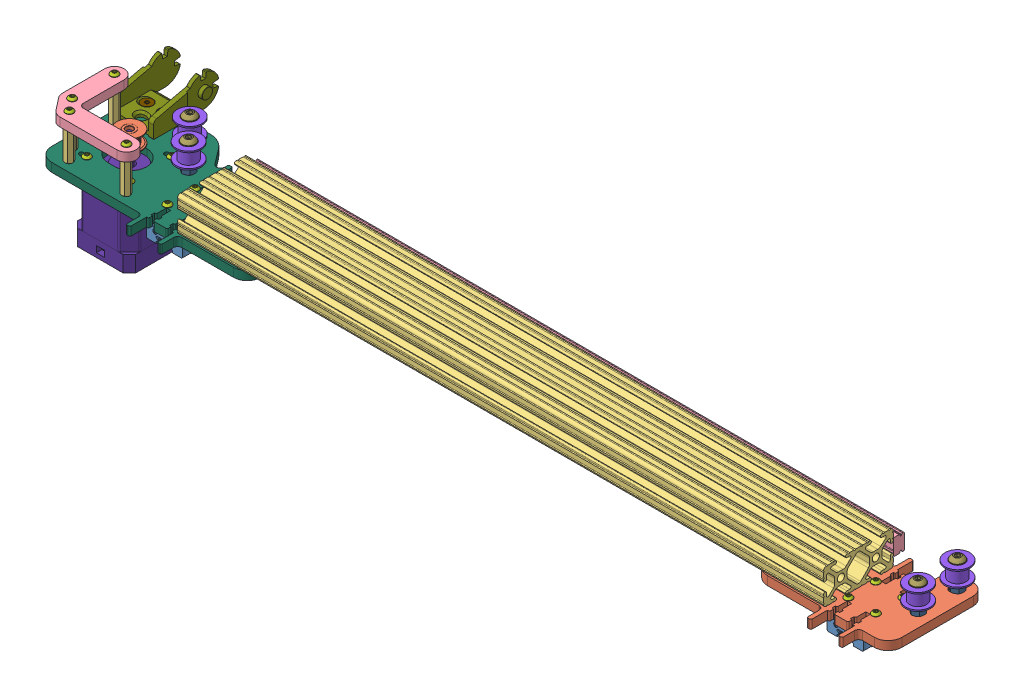
SolidWorks assembly X Axis, configuration Default. Lengths in mm.
Overall size (620.26 87.49 111.65).
113 component instances, 22 part files, 109 mates.
Components (placement in the parent):
- Hiwin-MGN12HZFC-1: Hiwin-MGN12HZFC [Default] at (247.7 -5 0) x (0 0 1) z (0 1 0) size (45.6 27 10)
- X Axis Idler Plate-1: X Axis Idler Plate [Default] at (222.3 5 22.7) x (-1 0 0) z (0 0 -1) size (97.84 6.35 82.44)
- Rail Mount-1: Rail Mount [Default] at (0 24.05 22.7) x (0 0 -1) z (-1 0 0) size (58.8 25.4 470)
  - 1020 Rail Support-1: 1020 Rail Support [1020] at (12.7 0 0) size (50.8 25.4 470)
  - Hiwin-MGNR12R470CM-1: Hiwin-MGNR12R470CM [Default] at (25.4 0 225) x (0 0 -1) z (1 0 0) size (470 12 8.07)
  - 91290A115_M3x10 BLACK-OXIDE CLASS 12.9 SOCKET HEAD CAP SCREW-20: 91290A115_M3x10 BLACK-OXIDE CLASS 12.9 SOCKET HEAD CAP SCREW [91290A115] at (18.9 0 225) x (0 0 1) z (-1 0 0) size (5.5 5.5 13.21)
  - 91290A115_M3x10 BLACK-OXIDE CLASS 12.9 SOCKET HEAD CAP SCREW-21: 91290A115_M3x10 BLACK-OXIDE CLASS 12.9 SOCKET HEAD CAP SCREW [91290A115] at (18.9 0 200) x (0 0 1) z (-1 0 0) size (5.5 5.5 13.21)
  - 91290A115_M3x10 BLACK-OXIDE CLASS 12.9 SOCKET HEAD CAP SCREW-22: 91290A115_M3x10 BLACK-OXIDE CLASS 12.9 SOCKET HEAD CAP SCREW [91290A115] at (18.9 0 175) x (0 0 1) z (-1 0 0) size (5.5 5.5 13.21)
  - 91290A115_M3x10 BLACK-OXIDE CLASS 12.9 SOCKET HEAD CAP SCREW-23: 91290A115_M3x10 BLACK-OXIDE CLASS 12.9 SOCKET HEAD CAP SCREW [91290A115] at (18.9 0 150) x (0 0 1) z (-1 0 0) size (5.5 5.5 13.21)
  - 91290A115_M3x10 BLACK-OXIDE CLASS 12.9 SOCKET HEAD CAP SCREW-24: 91290A115_M3x10 BLACK-OXIDE CLASS 12.9 SOCKET HEAD CAP SCREW [91290A115] at (18.9 0 125) x (0 0 1) z (-1 0 0) size (5.5 5.5 13.21)
  - 91290A115_M3x10 BLACK-OXIDE CLASS 12.9 SOCKET HEAD CAP SCREW-25: 91290A115_M3x10 BLACK-OXIDE CLASS 12.9 SOCKET HEAD CAP SCREW [91290A115] at (18.9 0 100) x (0 0 1) z (-1 0 0) size (5.5 5.5 13.21)
  - 91290A115_M3x10 BLACK-OXIDE CLASS 12.9 SOCKET HEAD CAP SCREW-26: 91290A115_M3x10 BLACK-OXIDE CLASS 12.9 SOCKET HEAD CAP SCREW [91290A115] at (18.9 0 75) x (0 0 1) z (-1 0 0) size (5.5 5.5 13.21)
  - 91290A115_M3x10 BLACK-OXIDE CLASS 12.9 SOCKET HEAD CAP SCREW-27: 91290A115_M3x10 BLACK-OXIDE CLASS 12.9 SOCKET HEAD CAP SCREW [91290A115] at (18.9 0 50) x (0 0 1) z (-1 0 0) size (5.5 5.5 13.21)
  - 91290A115_M3x10 BLACK-OXIDE CLASS 12.9 SOCKET HEAD CAP SCREW-28: 91290A115_M3x10 BLACK-OXIDE CLASS 12.9 SOCKET HEAD CAP SCREW [91290A115] at (18.9 0 25) x (0 0 1) z (-1 0 0) size (5.5 5.5 13.21)
  - 91290A115_M3x10 BLACK-OXIDE CLASS 12.9 SOCKET HEAD CAP SCREW-29: 91290A115_M3x10 BLACK-OXIDE CLASS 12.9 SOCKET HEAD CAP SCREW [91290A115] at (18.9 0 0) x (0 0 1) z (-1 0 0) size (5.5 5.5 13.21)
  - 91290A115_M3x10 BLACK-OXIDE CLASS 12.9 SOCKET HEAD CAP SCREW-30: 91290A115_M3x10 BLACK-OXIDE CLASS 12.9 SOCKET HEAD CAP SCREW [91290A115] at (18.9 0 -25) x (0 0 1) z (-1 0 0) size (5.5 5.5 13.21)
  - 91290A115_M3x10 BLACK-OXIDE CLASS 12.9 SOCKET HEAD CAP SCREW-31: 91290A115_M3x10 BLACK-OXIDE CLASS 12.9 SOCKET HEAD CAP SCREW [91290A115] at (18.9 0 -50) x (0 0 1) z (-1 0 0) size (5.5 5.5 13.21)
  - 91290A115_M3x10 BLACK-OXIDE CLASS 12.9 SOCKET HEAD CAP SCREW-32: 91290A115_M3x10 BLACK-OXIDE CLASS 12.9 SOCKET HEAD CAP SCREW [91290A115] at (18.9 0 -75) x (0 0 1) z (-1 0 0) size (5.5 5.5 13.21)
  - 91290A115_M3x10 BLACK-OXIDE CLASS 12.9 SOCKET HEAD CAP SCREW-33: 91290A115_M3x10 BLACK-OXIDE CLASS 12.9 SOCKET HEAD CAP SCREW [91290A115] at (18.9 0 -100) x (0 0 1) z (-1 0 0) size (5.5 5.5 13.21)
  - 91290A115_M3x10 BLACK-OXIDE CLASS 12.9 SOCKET HEAD CAP SCREW-34: 91290A115_M3x10 BLACK-OXIDE CLASS 12.9 SOCKET HEAD CAP SCREW [91290A115] at (18.9 0 -125) x (0 0 1) z (-1 0 0) size (5.5 5.5 13.21)
  - 91290A115_M3x10 BLACK-OXIDE CLASS 12.9 SOCKET HEAD CAP SCREW-35: 91290A115_M3x10 BLACK-OXIDE CLASS 12.9 SOCKET HEAD CAP SCREW [91290A115] at (18.9 0 -150) x (0 0 1) z (-1 0 0) size (5.5 5.5 13.21)
  - 91290A115_M3x10 BLACK-OXIDE CLASS 12.9 SOCKET HEAD CAP SCREW-36: 91290A115_M3x10 BLACK-OXIDE CLASS 12.9 SOCKET HEAD CAP SCREW [91290A115] at (18.9 0 -175) x (0 0 1) z (-1 0 0) size (5.5 5.5 13.21)
  - 91290A115_M3x10 BLACK-OXIDE CLASS 12.9 SOCKET HEAD CAP SCREW-37: 91290A115_M3x10 BLACK-OXIDE CLASS 12.9 SOCKET HEAD CAP SCREW [91290A115] at (18.9 0 -200) x (0 0 1) z (-1 0 0) size (5.5 5.5 13.21)
  - 91290A115_M3x10 BLACK-OXIDE CLASS 12.9 SOCKET HEAD CAP SCREW-38: 91290A115_M3x10 BLACK-OXIDE CLASS 12.9 SOCKET HEAD CAP SCREW [91290A115] at (18.9 0 -225) x (0 0 1) z (-1 0 0) size (5.5 5.5 13.21)
  - M3 T slot nut-ebay262350716437-1: M3 T slot nut-ebay262350716437 [Default] at (23.6902 0 228) x (0 1 0) z (0 0 -1) size (10 4 6)
  - M3 T slot nut-ebay262350716437-2: M3 T slot nut-ebay262350716437 [Default] at (23.6902 0 203) x (0 1 0) z (0 0 -1) size (10 4 6)
  - M3 T slot nut-ebay262350716437-3: M3 T slot nut-ebay262350716437 [Default] at (23.6902 0 178) x (0 1 0) z (0 0 -1) size (10 4 6)
  - M3 T slot nut-ebay262350716437-4: M3 T slot nut-ebay262350716437 [Default] at (23.6902 0 153) x (0 1 0) z (0 0 -1) size (10 4 6)
  - M3 T slot nut-ebay262350716437-5: M3 T slot nut-ebay262350716437 [Default] at (23.6902 0 128) x (0 1 0) z (0 0 -1) size (10 4 6)
  - M3 T slot nut-ebay262350716437-6: M3 T slot nut-ebay262350716437 [Default] at (23.6902 0 103) x (0 1 0) z (0 0 -1) size (10 4 6)
  - M3 T slot nut-ebay262350716437-7: M3 T slot nut-ebay262350716437 [Default] at (23.6902 0 78) x (0 1 0) z (0 0 -1) size (10 4 6)
  - M3 T slot nut-ebay262350716437-8: M3 T slot nut-ebay262350716437 [Default] at (23.6902 0 53) x (0 1 0) z (0 0 -1) size (10 4 6)
  - M3 T slot nut-ebay262350716437-9: M3 T slot nut-ebay262350716437 [Default] at (23.6902 0 28) x (0 1 0) z (0 0 -1) size (10 4 6)
  - M3 T slot nut-ebay262350716437-10: M3 T slot nut-ebay262350716437 [Default] at (23.6902 0 3) x (0 1 0) z (0 0 -1) size (10 4 6)
  - M3 T slot nut-ebay262350716437-11: M3 T slot nut-ebay262350716437 [Default] at (23.6902 0 -22) x (0 1 0) z (0 0 -1) size (10 4 6)
  - M3 T slot nut-ebay262350716437-12: M3 T slot nut-ebay262350716437 [Default] at (23.6902 0 -47) x (0 1 0) z (0 0 -1) size (10 4 6)
  - M3 T slot nut-ebay262350716437-13: M3 T slot nut-ebay262350716437 [Default] at (23.6902 0 -72) x (0 1 0) z (0 0 -1) size (10 4 6)
  - M3 T slot nut-ebay262350716437-14: M3 T slot nut-ebay262350716437 [Default] at (23.6902 0 -97) x (0 1 0) z (0 0 -1) size (10 4 6)
  - M3 T slot nut-ebay262350716437-15: M3 T slot nut-ebay262350716437 [Default] at (23.6902 0 -122) x (0 1 0) z (0 0 -1) size (10 4 6)
  - M3 T slot nut-ebay262350716437-16: M3 T slot nut-ebay262350716437 [Default] at (23.6902 0 -147) x (0 1 0) z (0 0 -1) size (10 4 6)
  - M3 T slot nut-ebay262350716437-17: M3 T slot nut-ebay262350716437 [Default] at (23.6902 0 -172) x (0 1 0) z (0 0 -1) size (10 4 6)
  - M3 T slot nut-ebay262350716437-18: M3 T slot nut-ebay262350716437 [Default] at (23.6902 0 -197) x (0 1 0) z (0 0 -1) size (10 4 6)
  - M3 T slot nut-ebay262350716437-19: M3 T slot nut-ebay262350716437 [Default] at (23.6902 0 -222) x (0 1 0) z (0 0 -1) size (10 4 6)
- 91239A115_M3x10 CLASS 10.9 STL BUTTON-HEAD SOCKET CAP SCREW-14: 91239A115_M3x10 CLASS 10.9 STL BUTTON-HEAD SOCKET CAP SCREW [91239A115] at (237.7 13 32.7) x (1 0 0) z (0 1 0) size (5.7 5.7 11.96)
- 91239A115_M3x10 CLASS 10.9 STL BUTTON-HEAD SOCKET CAP SCREW-17: 91239A115_M3x10 CLASS 10.9 STL BUTTON-HEAD SOCKET CAP SCREW [91239A115] at (237.7 13 12.7) x (1 0 0) z (0 1 0) size (5.7 5.7 11.96)
- 91239A115_M3x10 CLASS 10.9 STL BUTTON-HEAD SOCKET CAP SCREW-15: 91239A115_M3x10 CLASS 10.9 STL BUTTON-HEAD SOCKET CAP SCREW [91239A115] at (257.7 13 32.7) x (1 0 0) z (0 1 0) size (5.7 5.7 11.96)
- 91239A115_M3x10 CLASS 10.9 STL BUTTON-HEAD SOCKET CAP SCREW-16: 91239A115_M3x10 CLASS 10.9 STL BUTTON-HEAD SOCKET CAP SCREW [91239A115] at (257.7 13 12.7) x (1 0 0) z (0 1 0) size (5.7 5.7 11.96)
- 20T Idler Pulley wBearing-1: 20T Idler Pulley wBearing [Default] at (272.04 24.05 16.34) x (0.994803 0 0.101817) z (-0.101817 0 0.994803) size (18 33.32 18)
  - Powge 20T Idler Pulley-1: Powge 20T Idler Pulley [Default] at origin size (18 12 18)
  - 7804K106_STAINLESS STEEL BALL BEARING-1: 7804K106_STAINLESS STEEL BALL BEARING [7804K106] at (0 4 0) x (1 0 0) z (0 -1 0) size (10 10 4)
  - 7804K106_STAINLESS STEEL BALL BEARING-2: 7804K106_STAINLESS STEEL BALL BEARING [7804K106] at (0 -4 0) x (-1 0 0) z (0 1 0) size (10 10 4)
  - 90591A146_M5 ZINC PLATED STEEL HEX NUT-1: 90591A146_M5 ZINC PLATED STEEL HEX NUT [90591A146] at (0 -10.7 0) x (1 0 0) z (0 1 0) size (8 9.24 4.46)
  - 90695A037_M5 CLASS 04 STEEL THIN HEX NUT - DIN 439B-1: 90695A037_M5 CLASS 04 STEEL THIN HEX NUT - DIN 439B [90695A037] at (0 -7.35 0) size (8 3.32 9.24)
  - 91239A236_M5x30 CLASS 10.9 STL BUTTON-HEAD SOCKET CAP SCREW-1: 91239A236_M5x30 CLASS 10.9 STL BUTTON-HEAD SOCKET CAP SCREW [91239A236] at (0 8.75 0) x (1 0 0) z (0 1 0) size (9.5 9.5 33.32)
- 90576A104_M5 ZINC-PLATED CLASS 8 STL NYLON-INSERT LOCKNUT-1: 90576A104_M5 ZINC-PLATED CLASS 8 STL NYLON-INSERT LOCKNUT [90576A104] at (272.04 5 16.34) x (0.923728 0 -0.383049) z (-0.383049 0 -0.923728) size (8 5.15 9.24)
- 20T Idler Pulley wBearing-2: 20T Idler Pulley wBearing [Default] at (272.04 24.05 -12.34) x (0.994803 0 0.101817) z (-0.101817 0 0.994803) size (18 33.32 18)
  - Powge 20T Idler Pulley-1: Powge 20T Idler Pulley [Default] at origin size (18 12 18)
  - 7804K106_STAINLESS STEEL BALL BEARING-1: 7804K106_STAINLESS STEEL BALL BEARING [7804K106] at (0 4 0) x (1 0 0) z (0 -1 0) size (10 10 4)
  - 7804K106_STAINLESS STEEL BALL BEARING-2: 7804K106_STAINLESS STEEL BALL BEARING [7804K106] at (0 -4 0) x (-1 0 0) z (0 1 0) size (10 10 4)
  - 90591A146_M5 ZINC PLATED STEEL HEX NUT-1: 90591A146_M5 ZINC PLATED STEEL HEX NUT [90591A146] at (0 -10.7 0) x (1 0 0) z (0 1 0) size (8 9.24 4.46)
  - 90695A037_M5 CLASS 04 STEEL THIN HEX NUT - DIN 439B-1: 90695A037_M5 CLASS 04 STEEL THIN HEX NUT - DIN 439B [90695A037] at (0 -7.35 0) size (8 3.32 9.24)
  - 91239A236_M5x30 CLASS 10.9 STL BUTTON-HEAD SOCKET CAP SCREW-1: 91239A236_M5x30 CLASS 10.9 STL BUTTON-HEAD SOCKET CAP SCREW [91239A236] at (0 8.75 0) x (1 0 0) z (0 1 0) size (9.5 9.5 33.32)
- 90576A104_M5 ZINC-PLATED CLASS 8 STL NYLON-INSERT LOCKNUT-2: 90576A104_M5 ZINC-PLATED CLASS 8 STL NYLON-INSERT LOCKNUT [90576A104] at (272.04 5 -12.34) x (0.923728 0 -0.383049) z (-0.383049 0 -0.923728) size (8 5.15 9.24)
- 91239A228_M5x12 CLASS 10.9 STL BUTTON-HEAD SOCKET CAP SCREW-1: 91239A228_M5x12 CLASS 10.9 STL BUTTON-HEAD SOCKET CAP SCREW [91239A228] at (196.9 2.25 10) x (0.396762 0 -0.917922) z (0 -1 0) size (9.5 9.5 15.22)
- 91239A228_M5x12 CLASS 10.9 STL BUTTON-HEAD SOCKET CAP SCREW-2: 91239A228_M5x12 CLASS 10.9 STL BUTTON-HEAD SOCKET CAP SCREW [91239A228] at (222.3 2.25 10) x (1 0 0) z (0 -1 0) size (9.5 9.5 15.22)
- 91239A228_M5x12 CLASS 10.9 STL BUTTON-HEAD SOCKET CAP SCREW-3: 91239A228_M5x12 CLASS 10.9 STL BUTTON-HEAD SOCKET CAP SCREW [91239A228] at (196.9 2.25 35.4) x (1 0 0) z (0 -1 0) size (9.5 9.5 15.22)
- 91239A228_M5x12 CLASS 10.9 STL BUTTON-HEAD SOCKET CAP SCREW-4: 91239A228_M5x12 CLASS 10.9 STL BUTTON-HEAD SOCKET CAP SCREW [91239A228] at (222.3 2.25 35.4) x (1 0 0) z (0 -1 0) size (9.5 9.5 15.22)
- X Axis Motor Plate-1: X Axis Motor Plate [Default] at (-222.3 5 22.7) x (-1 0 0) z (0 0 -1) size (152.42 6.35 87.44)
- Hiwin-MGN12HZFC-2: Hiwin-MGN12HZFC [Default] at (-247.7 -5 0) x (0 0 1) z (0 1 0) size (45.6 27 10)
- 91239A115_M3x10 CLASS 10.9 STL BUTTON-HEAD SOCKET CAP SCREW-18: 91239A115_M3x10 CLASS 10.9 STL BUTTON-HEAD SOCKET CAP SCREW [91239A115] at (-257.7 13 32.7) x (1 0 0) z (0 1 0) size (5.7 5.7 11.96)
- 91239A115_M3x10 CLASS 10.9 STL BUTTON-HEAD SOCKET CAP SCREW-8: 91239A115_M3x10 CLASS 10.9 STL BUTTON-HEAD SOCKET CAP SCREW [91239A115] at (-237.7 13 32.7) x (1 0 0) z (0 1 0) size (5.7 5.7 11.96)
- 91239A115_M3x10 CLASS 10.9 STL BUTTON-HEAD SOCKET CAP SCREW-7: 91239A115_M3x10 CLASS 10.9 STL BUTTON-HEAD SOCKET CAP SCREW [91239A115] at (-237.7 13 12.7) x (1 0 0) z (0 1 0) size (5.7 5.7 11.96)
- 91239A115_M3x10 CLASS 10.9 STL BUTTON-HEAD SOCKET CAP SCREW-12: 91239A115_M3x10 CLASS 10.9 STL BUTTON-HEAD SOCKET CAP SCREW [91239A115] at (-257.7 13 12.7) x (1 0 0) z (0 1 0) size (5.7 5.7 11.96)
- 20T Idler Pulley wBearing-3: 20T Idler Pulley wBearing [Default] at (-271.4 24.05 3.62) x (0.994803 0 0.101817) z (-0.101817 0 0.994803) size (18 33.32 18)
  - Powge 20T Idler Pulley-1: Powge 20T Idler Pulley [Default] at origin size (18 12 18)
  - 7804K106_STAINLESS STEEL BALL BEARING-1: 7804K106_STAINLESS STEEL BALL BEARING [7804K106] at (0 4 0) x (1 0 0) z (0 -1 0) size (10 10 4)
  - 7804K106_STAINLESS STEEL BALL BEARING-2: 7804K106_STAINLESS STEEL BALL BEARING [7804K106] at (0 -4 0) x (-1 0 0) z (0 1 0) size (10 10 4)
  - 90591A146_M5 ZINC PLATED STEEL HEX NUT-1: 90591A146_M5 ZINC PLATED STEEL HEX NUT [90591A146] at (0 -10.7 0) x (1 0 0) z (0 1 0) size (8 9.24 4.46)
  - 90695A037_M5 CLASS 04 STEEL THIN HEX NUT - DIN 439B-1: 90695A037_M5 CLASS 04 STEEL THIN HEX NUT - DIN 439B [90695A037] at (0 -7.35 0) size (8 3.32 9.24)
  - 91239A236_M5x30 CLASS 10.9 STL BUTTON-HEAD SOCKET CAP SCREW-1: 91239A236_M5x30 CLASS 10.9 STL BUTTON-HEAD SOCKET CAP SCREW [91239A236] at (0 8.75 0) x (1 0 0) z (0 1 0) size (9.5 9.5 33.32)
- 20T Idler Pulley wBearing-4: 20T Idler Pulley wBearing [Default] at (-286.5419 24.05 -12.34) x (0.994803 0 0.101817) z (-0.101817 0 0.994803) size (18 33.32 18)
  - Powge 20T Idler Pulley-1: Powge 20T Idler Pulley [Default] at origin size (18 12 18)
  - 7804K106_STAINLESS STEEL BALL BEARING-1: 7804K106_STAINLESS STEEL BALL BEARING [7804K106] at (0 4 0) x (1 0 0) z (0 -1 0) size (10 10 4)
  - 7804K106_STAINLESS STEEL BALL BEARING-2: 7804K106_STAINLESS STEEL BALL BEARING [7804K106] at (0 -4 0) x (-1 0 0) z (0 1 0) size (10 10 4)
  - 90591A146_M5 ZINC PLATED STEEL HEX NUT-1: 90591A146_M5 ZINC PLATED STEEL HEX NUT [90591A146] at (0 -10.7 0) x (1 0 0) z (0 1 0) size (8 9.24 4.46)
  - 90695A037_M5 CLASS 04 STEEL THIN HEX NUT - DIN 439B-1: 90695A037_M5 CLASS 04 STEEL THIN HEX NUT - DIN 439B [90695A037] at (0 -7.35 0) size (8 3.32 9.24)
  - 91239A236_M5x30 CLASS 10.9 STL BUTTON-HEAD SOCKET CAP SCREW-1: 91239A236_M5x30 CLASS 10.9 STL BUTTON-HEAD SOCKET CAP SCREW [91239A236] at (0 8.75 0) x (1 0 0) z (0 1 0) size (9.5 9.5 33.32)
- Drag Chain 18x25mm End-1: Drag Chain 18x25mm End [Default] at (-319.9712 11.35 -3.16) size (36.5 22.67 48.39)
- Nema17-1200mA-Stepper-1: Nema17-1200mA-Stepper [Default] at (-301.7597 -43 16.34) size (42.3 70.03 42.3)
- 91239A115_M3x10 CLASS 10.9 STL BUTTON-HEAD SOCKET CAP SCREW-9: 91239A115_M3x10 CLASS 10.9 STL BUTTON-HEAD SOCKET CAP SCREW [91239A115] at (-286.2597 13 31.84) x (1 0 0) z (0 1 0) size (5.7 5.7 11.96)
- 91239A115_M3x10 CLASS 10.9 STL BUTTON-HEAD SOCKET CAP SCREW-10: 91239A115_M3x10 CLASS 10.9 STL BUTTON-HEAD SOCKET CAP SCREW [91239A115] at (-317.2597 13 31.84) x (1 0 0) z (0 1 0) size (5.7 5.7 11.96)
- 91239A115_M3x10 CLASS 10.9 STL BUTTON-HEAD SOCKET CAP SCREW-11: 91239A115_M3x10 CLASS 10.9 STL BUTTON-HEAD SOCKET CAP SCREW [91239A115] at (-317.2597 13 0.84) x (1 0 0) z (0 1 0) size (5.7 5.7 11.96)
- 91239A115_M3x10 CLASS 10.9 STL BUTTON-HEAD SOCKET CAP SCREW-13: 91239A115_M3x10 CLASS 10.9 STL BUTTON-HEAD SOCKET CAP SCREW [91239A115] at (-286.2597 13 0.84) x (1 0 0) z (0 1 0) size (5.7 5.7 11.96)
- 91294A194_M4x16 BLACK ALLOY STEEL FLAT-HEAD SOCKET CAP SCREW-4: 91294A194_M4x16 BLACK ALLOY STEEL FLAT-HEAD SOCKET CAP SCREW [91294A194] at (-313.7212 14.85 -20.91) x (1 0 0) z (0 1 0) size (8 8 16.42)
- 91294A194_M4x16 BLACK ALLOY STEEL FLAT-HEAD SOCKET CAP SCREW-5: 91294A194_M4x16 BLACK ALLOY STEEL FLAT-HEAD SOCKET CAP SCREW [91294A194] at (-326.2212 14.85 -20.91) x (1 0 0) z (0 1 0) size (8 8 16.42)
- 90576A103_M4 ZINC-PLATED CLASS 8 STL NYLON-INSERT LOCKNUT-1: 90576A103_M4 ZINC-PLATED CLASS 8 STL NYLON-INSERT LOCKNUT [90576A103] at (-313.7212 5 -20.91) x (-0.837169 0 -0.546944) z (-0.546944 0 0.837169) size (7 5.12 8.08)
- 90576A103_M4 ZINC-PLATED CLASS 8 STL NYLON-INSERT LOCKNUT-2: 90576A103_M4 ZINC-PLATED CLASS 8 STL NYLON-INSERT LOCKNUT [90576A103] at (-326.2212 5 -20.91) x (0.272867 0 0.962052) z (0.962052 0 -0.272867) size (7 5.12 8.08)
- GT2_20tooth-1: GT2_20tooth [Default] at (-301.7597 11.55 16.34) x (0 1 0) z (-0.782139 0 -0.623104) size (17.5 18 18)
- 90576A103_M4 ZINC-PLATED CLASS 8 STL NYLON-INSERT LOCKNUT-3: 90576A103_M4 ZINC-PLATED CLASS 8 STL NYLON-INSERT LOCKNUT [90576A103] at (-286.5419 5 -12.34) x (-0.837169 0 -0.546944) z (-0.546944 0 0.837169) size (7 5.12 8.08)
- 90576A103_M4 ZINC-PLATED CLASS 8 STL NYLON-INSERT LOCKNUT-4: 90576A103_M4 ZINC-PLATED CLASS 8 STL NYLON-INSERT LOCKNUT [90576A103] at (-271.4 5 3.62) x (-0.837169 0 -0.546944) z (-0.546944 0 0.837169) size (7 5.12 8.08)
- M4x25 standoff-1: M4x25 standoff [Default] at (-321.1212 11.35 40.84) size (6.93 25 6)
- M4x25 standoff-2: M4x25 standoff [Default] at (-327.8666 11.35 31.84) size (6.93 25 6)
- M4x25 standoff-3: M4x25 standoff [Default] at (-327.8666 11.35 1.09) size (6.93 25 6)
- M4x25 standoff-4: M4x25 standoff [Default] at (-279.6212 11.35 40.84) size (6.93 25 6)
- 91239A115_M3x10 CLASS 10.9 STL BUTTON-HEAD SOCKET CAP SCREW-22: 91239A115_M3x10 CLASS 10.9 STL BUTTON-HEAD SOCKET CAP SCREW [91239A115] at (-327.8666 3.35 1.09) x (-0.837169 0 -0.546944) z (0 -1 0) size (5.7 5.7 11.96)
- 91239A115_M3x10 CLASS 10.9 STL BUTTON-HEAD SOCKET CAP SCREW-23: 91239A115_M3x10 CLASS 10.9 STL BUTTON-HEAD SOCKET CAP SCREW [91239A115] at (-327.8666 3.35 31.84) x (-0.837169 0 -0.546944) z (0 -1 0) size (5.7 5.7 11.96)
- 91239A115_M3x10 CLASS 10.9 STL BUTTON-HEAD SOCKET CAP SCREW-24: 91239A115_M3x10 CLASS 10.9 STL BUTTON-HEAD SOCKET CAP SCREW [91239A115] at (-321.1212 3.35 40.84) x (-0.837169 0 -0.546944) z (0 -1 0) size (5.7 5.7 11.96)
- 91239A115_M3x10 CLASS 10.9 STL BUTTON-HEAD SOCKET CAP SCREW-25: 91239A115_M3x10 CLASS 10.9 STL BUTTON-HEAD SOCKET CAP SCREW [91239A115] at (-279.6212 3.35 40.84) x (-0.837169 0 -0.546944) z (0 -1 0) size (5.7 5.7 11.96)
- X Axis Cable Guide Top-1: X Axis Cable Guide Top [Default] at (-320.8666 36.35 40.84) x (1 0 0) z (0 1 0) size (62.5 53.75 6.35)
- 91239A115_M3x10 CLASS 10.9 STL BUTTON-HEAD SOCKET CAP SCREW-26: 91239A115_M3x10 CLASS 10.9 STL BUTTON-HEAD SOCKET CAP SCREW [91239A115] at (-327.8666 44.35 1.09) x (1 0 0) z (0 1 0) size (5.7 5.7 11.96)
- 91239A115_M3x10 CLASS 10.9 STL BUTTON-HEAD SOCKET CAP SCREW-27: 91239A115_M3x10 CLASS 10.9 STL BUTTON-HEAD SOCKET CAP SCREW [91239A115] at (-327.8666 44.35 31.84) x (1 0 0) z (0 1 0) size (5.7 5.7 11.96)
- 91239A115_M3x10 CLASS 10.9 STL BUTTON-HEAD SOCKET CAP SCREW-28: 91239A115_M3x10 CLASS 10.9 STL BUTTON-HEAD SOCKET CAP SCREW [91239A115] at (-320.8666 44.35 40.84) x (1 0 0) z (0 1 0) size (5.7 5.7 11.96)
- 91239A115_M3x10 CLASS 10.9 STL BUTTON-HEAD SOCKET CAP SCREW-29: 91239A115_M3x10 CLASS 10.9 STL BUTTON-HEAD SOCKET CAP SCREW [91239A115] at (-279.3666 44.35 40.84) x (1 0 0) z (0 1 0) size (5.7 5.7 11.96)
Mates (geometry in assembly coordinates):
- Coincident1: coincident anti-aligned: plane of Hiwin-MGN12HZFC-1 through (254.1 5 6.5) normal (0 1 0); plane of X Axis Idler Plate-1 through (222.3 5 22.7) normal (0 -1 0)
- Concentric3: concentric anti-aligned: cylinder of Hiwin-MGN12HZFC-1 through (237.7 1.0625 12.7) axis (0 -1 0) radius 1.2295; cylinder of X Axis Idler Plate-1 through (237.7 11.35 12.7) axis (0 1 0) radius 1.7
- Concentric4: concentric anti-aligned: cylinder of Hiwin-MGN12HZFC-1 through (257.7 1.0625 32.7) axis (0 -1 0) radius 1.2295; cylinder of X Axis Idler Plate-1 through (257.7 11.35 32.7) axis (0 1 0) radius 1.7
- Parallel1: parallel aligned: plane of X Axis Idler Plate-1 through (184.2 11.35 -2.7) normal (0 0 -1); plane of Rail Mount-1/Hiwin-MGNR12R470CM-1 through (235 29.55 -10.7) normal (0 0 -1)
- Coincident3: coincident anti-aligned: plane of X Axis Idler Plate-1 through (222.3 11.35 22.7) normal (0 1 0); plane of Rail Mount-1/1020 Rail Support-1 through (235 11.35 20.5664) normal (0 -1 0)
- Coincident4: coincident aligned: plane of X Axis Idler Plate-1 through (184.2 11.35 48.1) normal (0 0 1); plane of Rail Mount-1/1020 Rail Support-1 through (235 14.4996 48.1) normal (0 0 1)
- Distance1: distance = 50.8 mm anti-aligned: plane of Rail Mount-1/1020 Rail Support-1 through (235 12.399 5.7125) normal (1 0 0); plane of X Axis Idler Plate-1 through (184.2 11.35 -2.7) normal (-1 0 0)
- Coincident6: coincident anti-aligned: plane of X Axis Idler Plate-1 through (222.3 11.35 22.7) normal (0 1 0); plane of 91239A115_M3x10 CLASS 10.9 STL BUTTON-HEAD SOCKET CAP SCREW-14 through (237.7 11.35 35.55) normal (0 -1 0)
- Concentric5: concentric aligned: cylinder of X Axis Idler Plate-1 through (237.7 11.35 32.7) axis (0 1 0) radius 1.7; circle of 91239A115_M3x10 CLASS 10.9 STL BUTTON-HEAD SOCKET CAP SCREW-14
- Concentric6: concentric aligned: cylinder of X Axis Idler Plate-1 through (237.7 11.35 12.7) axis (0 1 0) radius 1.7; circle of 91239A115_M3x10 CLASS 10.9 STL BUTTON-HEAD SOCKET CAP SCREW-17
- Concentric7: concentric aligned: cylinder of X Axis Idler Plate-1 through (257.7 11.35 12.7) axis (0 1 0) radius 1.7; circle of 91239A115_M3x10 CLASS 10.9 STL BUTTON-HEAD SOCKET CAP SCREW-16
- Concentric8: concentric aligned: cylinder of X Axis Idler Plate-1 through (257.7 11.35 32.7) axis (0 1 0) radius 1.7; circle of 91239A115_M3x10 CLASS 10.9 STL BUTTON-HEAD SOCKET CAP SCREW-15
- Coincident7: coincident aligned: plane of 91239A115_M3x10 CLASS 10.9 STL BUTTON-HEAD SOCKET CAP SCREW-14 through (237.7 13 34.2) normal (0 1 0); plane of 91239A115_M3x10 CLASS 10.9 STL BUTTON-HEAD SOCKET CAP SCREW-17 through (237.7 13 14.2) normal (0 1 0)
- Coincident8: coincident aligned: plane of 91239A115_M3x10 CLASS 10.9 STL BUTTON-HEAD SOCKET CAP SCREW-14 through (237.7 13 34.2) normal (0 1 0); plane of 91239A115_M3x10 CLASS 10.9 STL BUTTON-HEAD SOCKET CAP SCREW-16 through (257.7 13 14.2) normal (0 1 0)
- Coincident9: coincident aligned: plane of 91239A115_M3x10 CLASS 10.9 STL BUTTON-HEAD SOCKET CAP SCREW-14 through (237.7 13 34.2) normal (0 1 0); plane of 91239A115_M3x10 CLASS 10.9 STL BUTTON-HEAD SOCKET CAP SCREW-15 through (257.7 13 34.2) normal (0 1 0)
- Coincident11: coincident anti-aligned: plane of X Axis Idler Plate-1; plane of ? through (16.34 21.4 16.35) normal (0 0 -1)
- Coincident12: coincident anti-aligned: plane of 20T Idler Pulley wBearing-1/7804K106_STAINLESS STEEL BALL BEARING-2; plane of ? through (16.34 21.4 22.7) normal (0 0 1)
- Concentric10: concentric aligned: cylinder of X Axis Idler Plate-1 through (16.34 21.4 16.35) axis (0 0 1) radius 2.75; cylinder of ? through (16.34 21.4 16.35) axis (0 0 1) radius 2.6
- Coincident13: coincident anti-aligned: plane of X Axis Idler Plate-1 through (222.3 11.35 22.7) normal (0 1 0); plane of 20T Idler Pulley wBearing-1/90591A146_M5 ZINC PLATED STEEL HEX NUT-1 through (268.2959 11.35 13.6353) normal (0 -1 0)
- Coincident14: coincident anti-aligned: plane of X Axis Idler Plate-1 through (222.3 5 22.7) normal (0 -1 0); plane of 90576A104_M5 ZINC-PLATED CLASS 8 STL NYLON-INSERT LOCKNUT-1 through (270.9989 5 24.272) normal (0 1 0)
- Coincident15: coincident anti-aligned: plane of X Axis Idler Plate-1 through (222.3 11.35 22.7) normal (0 1 0); plane of 20T Idler Pulley wBearing-2/90591A146_M5 ZINC PLATED STEEL HEX NUT-1 through (268.2959 11.35 -15.0447) normal (0 -1 0)
- Coincident16: coincident anti-aligned: plane of X Axis Idler Plate-1 through (222.3 5 22.7) normal (0 -1 0); plane of 90576A104_M5 ZINC-PLATED CLASS 8 STL NYLON-INSERT LOCKNUT-2 through (270.9989 5 -4.408) normal (0 1 0)
- Concentric13: concentric aligned: cylinder of 20T Idler Pulley wBearing-2/Powge 20T Idler Pulley-1 through (272.04 30.05 -12.34) axis (0 1 0) radius 6.05; cylinder of 90576A104_M5 ZINC-PLATED CLASS 8 STL NYLON-INSERT LOCKNUT-2 through (272.04 0.7571 -12.34) axis (0 1 0) radius 2.1277
- Concentric14: concentric aligned: cylinder of X Axis Idler Plate-1 through (272.04 5 16.34) axis (0 1 0) radius 2.65; cylinder of 20T Idler Pulley wBearing-1/Powge 20T Idler Pulley-1 through (272.04 30.05 16.34) axis (0 1 0) radius 6.05
- Concentric15: concentric aligned: cylinder of 20T Idler Pulley wBearing-1/Powge 20T Idler Pulley-1 through (272.04 30.05 16.34) axis (0 1 0) radius 6.05; cylinder of 90576A104_M5 ZINC-PLATED CLASS 8 STL NYLON-INSERT LOCKNUT-1 through (272.04 0.7571 16.34) axis (0 1 0) radius 2.1277
- Concentric17: concentric aligned: cylinder of X Axis Idler Plate-1 through (272.04 5 -12.34) axis (0 1 0) radius 2.65; cylinder of 20T Idler Pulley wBearing-2/Powge 20T Idler Pulley-1 through (272.04 30.05 -12.34) axis (0 1 0) radius 6.05
- Coincident17: coincident anti-aligned: plane of Hiwin-MGN12HZFC-1 through (242.2 0 6.5) normal (0 -1 0); plane of assembly through (0 0 0) normal (0 1 0)
- Coincident18: coincident anti-aligned: plane of Rail Mount-1 through (0 24.05 22.7) normal (-1 0 0); plane of assembly through (0 0 0) normal (1 0 0)
- Coincident19: coincident aligned: plane of Hiwin-MGN12HZFC-1; plane of assembly through (0 0 0) normal (0 0 1)
- Coincident20: coincident anti-aligned: plane of X Axis Idler Plate-1 through (222.3 5 22.7) normal (0 -1 0); plane of 91239A228_M5x12 CLASS 10.9 STL BUTTON-HEAD SOCKET CAP SCREW-1 through (192.5399 5 8.1154) normal (0 1 0)
- Concentric18: concentric anti-aligned: cylinder of X Axis Idler Plate-1 through (196.9 11.35 10) axis (0 1 0) radius 2.75; circle of 91239A228_M5x12 CLASS 10.9 STL BUTTON-HEAD SOCKET CAP SCREW-1
- Coincident21: coincident anti-aligned: plane of X Axis Idler Plate-1 through (222.3 5 22.7) normal (0 -1 0); plane of 91239A228_M5x12 CLASS 10.9 STL BUTTON-HEAD SOCKET CAP SCREW-2 through (222.3 5 5.25) normal (0 1 0)
- Coincident22: coincident anti-aligned: plane of X Axis Idler Plate-1 through (222.3 5 22.7) normal (0 -1 0); plane of 91239A228_M5x12 CLASS 10.9 STL BUTTON-HEAD SOCKET CAP SCREW-4 through (222.3 5 30.65) normal (0 1 0)
- Coincident23: coincident anti-aligned: plane of X Axis Idler Plate-1 through (222.3 5 22.7) normal (0 -1 0); plane of 91239A228_M5x12 CLASS 10.9 STL BUTTON-HEAD SOCKET CAP SCREW-3 through (196.9 5 30.65) normal (0 1 0)
- Concentric19: concentric anti-aligned: cylinder of X Axis Idler Plate-1 through (196.9 11.35 35.4) axis (0 1 0) radius 2.75; circle of 91239A228_M5x12 CLASS 10.9 STL BUTTON-HEAD SOCKET CAP SCREW-3
- Concentric20: concentric anti-aligned: cylinder of X Axis Idler Plate-1 through (222.3 11.35 10) axis (0 1 0) radius 2.75; circle of 91239A228_M5x12 CLASS 10.9 STL BUTTON-HEAD SOCKET CAP SCREW-2
- Concentric21: concentric anti-aligned: cylinder of X Axis Idler Plate-1 through (222.3 11.35 35.4) axis (0 1 0) radius 2.75; circle of 91239A228_M5x12 CLASS 10.9 STL BUTTON-HEAD SOCKET CAP SCREW-4
- Coincident24: coincident anti-aligned: plane of Rail Mount-1/1020 Rail Support-1 through (235 11.35 20.5664) normal (0 -1 0); plane of X Axis Motor Plate-1 through (-286.5419 11.35 -12.34) normal (0 1 0)
- Coincident25: coincident aligned: plane of Rail Mount-1/1020 Rail Support-1 through (235 14.4996 48.1) normal (0 0 1); plane of X Axis Motor Plate-1 through (-260.4 11.35 48.1) normal (0 0 1)
- Distance3: distance = 50.8 mm anti-aligned: plane of X Axis Motor Plate-1 through (-184.2 11.35 -2.7) normal (1 0 0); plane of Rail Mount-1/1020 Rail Support-1 through (-235 12.399 5.7125) normal (-1 0 0)
- Coincident27: coincident anti-aligned: plane of X Axis Motor Plate-1 through (-286.5419 5 -12.34) normal (0 -1 0); plane of Hiwin-MGN12HZFC-2 through (-241.3 5 6.5) normal (0 1 0)
- Concentric22: concentric anti-aligned: cylinder of X Axis Motor Plate-1 through (-237.7 11.35 32.7) axis (0 1 0) radius 1.7; cylinder of Hiwin-MGN12HZFC-2 through (-237.7 1.0625 32.7) axis (0 -1 0) radius 1.2295
- Concentric23: concentric anti-aligned: cylinder of X Axis Motor Plate-1 through (-257.7 11.35 12.7) axis (0 1 0) radius 1.7; cylinder of Hiwin-MGN12HZFC-2 through (-257.7 1.0625 12.7) axis (0 -1 0) radius 1.2295
- Concentric24: concentric aligned: cylinder of X Axis Motor Plate-1 through (-237.7 11.35 12.7) axis (0 1 0) radius 1.7; circle of 91239A115_M3x10 CLASS 10.9 STL BUTTON-HEAD SOCKET CAP SCREW-7
- Concentric25: concentric aligned: cylinder of X Axis Motor Plate-1 through (-257.7 11.35 12.7) axis (0 1 0) radius 1.7; circle of 91239A115_M3x10 CLASS 10.9 STL BUTTON-HEAD SOCKET CAP SCREW-12
- Concentric26: concentric aligned: cylinder of X Axis Motor Plate-1 through (-257.7 11.35 32.7) axis (0 1 0) radius 1.7; circle of 91239A115_M3x10 CLASS 10.9 STL BUTTON-HEAD SOCKET CAP SCREW-18
- Concentric27: concentric aligned: cylinder of X Axis Motor Plate-1 through (-237.7 11.35 32.7) axis (0 1 0) radius 1.7; circle of 91239A115_M3x10 CLASS 10.9 STL BUTTON-HEAD SOCKET CAP SCREW-8
- Coincident28: coincident anti-aligned: plane of X Axis Motor Plate-1 through (-286.5419 11.35 -12.34) normal (0 1 0); plane of 91239A115_M3x10 CLASS 10.9 STL BUTTON-HEAD SOCKET CAP SCREW-8 through (-237.7 11.35 35.55) normal (0 -1 0)
- Coincident29: coincident anti-aligned: plane of X Axis Motor Plate-1 through (-286.5419 11.35 -12.34) normal (0 1 0); plane of 91239A115_M3x10 CLASS 10.9 STL BUTTON-HEAD SOCKET CAP SCREW-7 through (-237.7 11.35 15.55) normal (0 -1 0)
- Coincident30: coincident anti-aligned: plane of X Axis Motor Plate-1 through (-286.5419 11.35 -12.34) normal (0 1 0); plane of 91239A115_M3x10 CLASS 10.9 STL BUTTON-HEAD SOCKET CAP SCREW-12 through (-257.7 11.35 15.55) normal (0 -1 0)
- Coincident31: coincident anti-aligned: plane of X Axis Motor Plate-1 through (-286.5419 11.35 -12.34) normal (0 1 0); plane of 91239A115_M3x10 CLASS 10.9 STL BUTTON-HEAD SOCKET CAP SCREW-18 through (-257.7 11.35 35.55) normal (0 -1 0)
- Concentric28: concentric aligned: cylinder of X Axis Motor Plate-1 through (-271.4 5 3.62) axis (0 1 0) radius 2.65; cylinder of 20T Idler Pulley wBearing-3/Powge 20T Idler Pulley-1 through (-271.4 30.05 3.62) axis (0 1 0) radius 6.05
- Concentric29: concentric aligned: cylinder of 20T Idler Pulley wBearing-4/Powge 20T Idler Pulley-1 through (-286.5419 30.05 -12.34) axis (0 1 0) radius 6.05; cylinder of X Axis Motor Plate-1 through (-286.5419 5 -12.34) axis (0 1 0) radius 2.65
- Coincident32: coincident anti-aligned: plane of X Axis Motor Plate-1 through (-286.5419 11.35 -12.34) normal (0 1 0); plane of 20T Idler Pulley wBearing-4/90591A146_M5 ZINC PLATED STEEL HEX NUT-1 through (-290.286 11.35 -15.0447) normal (0 -1 0)
- Coincident33: coincident anti-aligned: plane of X Axis Motor Plate-1 through (-286.5419 11.35 -12.34) normal (0 1 0); plane of 20T Idler Pulley wBearing-3/90591A146_M5 ZINC PLATED STEEL HEX NUT-1 through (-275.1441 11.35 0.9153) normal (0 -1 0)
- Concentric31: concentric aligned: cylinder of X Axis Motor Plate-1 through (-313.7212 5 -20.91) axis (0 1 0) radius 2.15; cylinder of Drag Chain 18x25mm End-1 through (-313.7212 11.35 -20.91) axis (0 1 0) radius 2.75
- Coincident34: coincident anti-aligned: plane of X Axis Motor Plate-1 through (-286.5419 11.35 -12.34) normal (0 1 0); plane of Drag Chain 18x25mm End-1 through (-303.7212 11.35 -3.16) normal (0 -1 0)
- Parallel2: parallel aligned: plane of X Axis Motor Plate-1 through (-336.6212 11.35 -27.34) normal (-1 0 0); plane of Drag Chain 18x25mm End-1 through (-336.2212 22.85 -40.3823) normal (-1 0 0)
- Coincident36: coincident anti-aligned: plane of X Axis Motor Plate-1 through (-286.5419 5 -12.34) normal (0 -1 0); plane of Nema17-1200mA-Stepper-1 through (-301.7597 5 16.34) normal (0 1 0)
- Parallel3: parallel aligned: plane of X Axis Motor Plate-1 through (-260.4 11.35 48.1) normal (0 0 1); plane of Nema17-1200mA-Stepper-1 through (-301.7597 5 37.49) normal (0 0 1)
- Distance5: distance = 10.61 mm aligned: plane of Nema17-1200mA-Stepper-1 through (-301.7597 5 37.49) normal (0 0 1); plane of X Axis Motor Plate-1 through (-260.4 11.35 48.1) normal (0 0 1)
- Coincident40: coincident anti-aligned: cylinder of Nema17-1200mA-Stepper-1 through (-286.2597 5 0.84) axis (0 -1 0) radius 1.5; circle of 91239A115_M3x10 CLASS 10.9 STL BUTTON-HEAD SOCKET CAP SCREW-13
- Coincident41: coincident anti-aligned: cylinder of Nema17-1200mA-Stepper-1 through (-286.2597 5 31.84) axis (0 -1 0) radius 1.5; circle of 91239A115_M3x10 CLASS 10.9 STL BUTTON-HEAD SOCKET CAP SCREW-9
- Coincident42: coincident anti-aligned: cylinder of Nema17-1200mA-Stepper-1 through (-317.2597 5 0.84) axis (0 -1 0) radius 1.5; circle of 91239A115_M3x10 CLASS 10.9 STL BUTTON-HEAD SOCKET CAP SCREW-11
- Coincident43: coincident anti-aligned: cylinder of Nema17-1200mA-Stepper-1 through (-317.2597 5 31.84) axis (0 -1 0) radius 1.5; circle of 91239A115_M3x10 CLASS 10.9 STL BUTTON-HEAD SOCKET CAP SCREW-10
- Coincident44: coincident anti-aligned: plane of X Axis Motor Plate-1 through (-286.5419 11.35 -12.34) normal (0 1 0); plane of 91239A115_M3x10 CLASS 10.9 STL BUTTON-HEAD SOCKET CAP SCREW-10 through (-317.2597 11.35 34.69) normal (0 -1 0)
- Coincident45: coincident anti-aligned: plane of X Axis Motor Plate-1 through (-286.5419 11.35 -12.34) normal (0 1 0); plane of 91239A115_M3x10 CLASS 10.9 STL BUTTON-HEAD SOCKET CAP SCREW-9 through (-286.2597 11.35 34.69) normal (0 -1 0)
- Coincident46: coincident anti-aligned: plane of X Axis Motor Plate-1 through (-286.5419 11.35 -12.34) normal (0 1 0); plane of 91239A115_M3x10 CLASS 10.9 STL BUTTON-HEAD SOCKET CAP SCREW-13 through (-286.2597 11.35 3.69) normal (0 -1 0)
- Coincident47: coincident anti-aligned: plane of X Axis Motor Plate-1 through (-286.5419 11.35 -12.34) normal (0 1 0); plane of 91239A115_M3x10 CLASS 10.9 STL BUTTON-HEAD SOCKET CAP SCREW-11 through (-317.2597 11.35 3.69) normal (0 -1 0)
- Coincident48: coincident aligned: cone of Drag Chain 18x25mm End-1 through (-321.345 13.3 -20.91) axis (0 -1 0); cone of ? through (-321.345 12.55 -20.91) axis (0 -1 0)
- Coincident49: coincident aligned: cone of Drag Chain 18x25mm End-1 through (-313.7212 13.3 -20.91) axis (0 -1 0); cone of 91294A194_M4x16 BLACK ALLOY STEEL FLAT-HEAD SOCKET CAP SCREW-4 through (-313.7212 12.55 -20.91) axis (0 -1 0)
- Coincident50: coincident aligned: cone of Drag Chain 18x25mm End-1 through (-326.2212 13.3 -20.91) axis (0 -1 0); cone of 91294A194_M4x16 BLACK ALLOY STEEL FLAT-HEAD SOCKET CAP SCREW-5 through (-326.2212 12.55 -20.91) axis (0 -1 0)
- Concentric33: concentric aligned: circle of 91294A194_M4x16 BLACK ALLOY STEEL FLAT-HEAD SOCKET CAP SCREW-4; circle of 90576A103_M4 ZINC-PLATED CLASS 8 STL NYLON-INSERT LOCKNUT-1
- Coincident51: coincident anti-aligned: plane of X Axis Motor Plate-1 through (-286.5419 5 -12.34) normal (0 -1 0); plane of 90576A103_M4 ZINC-PLATED CLASS 8 STL NYLON-INSERT LOCKNUT-1 through (-311.5108 5 -24.2934) normal (0 1 0)
- Coincident52: coincident anti-aligned: plane of X Axis Motor Plate-1 through (-286.5419 5 -12.34) normal (0 -1 0); plane of 90576A103_M4 ZINC-PLATED CLASS 8 STL NYLON-INSERT LOCKNUT-2 through (-330.1093 5 -19.8072) normal (0 1 0)
- Concentric34: concentric aligned: circle of 91294A194_M4x16 BLACK ALLOY STEEL FLAT-HEAD SOCKET CAP SCREW-5; cylinder of 90576A103_M4 ZINC-PLATED CLASS 8 STL NYLON-INSERT LOCKNUT-2 through (-326.2212 0.7571 -20.91) axis (0 1 0) radius 1.6796
- Concentric35: concentric anti-aligned: cylinder of Nema17-1200mA-Stepper-1 through (-301.7597 27 16.34) axis (0 -1 0) radius 2.5; cylinder of GT2_20tooth-1 through (-301.7597 11.55 16.34) axis (0 1 0) radius 2.5
- Distance6: distance = 1.5 mm aligned: plane of GT2_20tooth-1 through (-301.7597 20.55 16.34) normal (0 1 0); plane of 20T Idler Pulley wBearing-3/Powge 20T Idler Pulley-1 through (-280.3532 19.05 2.7036) normal (0 1 0)
- Concentric36: concentric aligned: cylinder of 20T Idler Pulley wBearing-3/Powge 20T Idler Pulley-1 through (-271.4 30.05 3.62) axis (0 1 0) radius 6.05; cylinder of 90576A103_M4 ZINC-PLATED CLASS 8 STL NYLON-INSERT LOCKNUT-4 through (-271.4 0.7571 3.62) axis (0 1 0) radius 1.6796
- Concentric37: concentric aligned: cylinder of 20T Idler Pulley wBearing-4/Powge 20T Idler Pulley-1 through (-286.5419 30.05 -12.34) axis (0 1 0) radius 6.05; cylinder of 90576A103_M4 ZINC-PLATED CLASS 8 STL NYLON-INSERT LOCKNUT-3 through (-286.5419 0.7571 -12.34) axis (0 1 0) radius 1.6796
- Coincident54: coincident anti-aligned: plane of X Axis Motor Plate-1 through (-286.5419 5 -12.34) normal (0 -1 0); plane of 90576A103_M4 ZINC-PLATED CLASS 8 STL NYLON-INSERT LOCKNUT-3 through (-284.3315 5 -15.7234) normal (0 1 0)
- Coincident55: coincident anti-aligned: plane of X Axis Motor Plate-1 through (-286.5419 5 -12.34) normal (0 -1 0); plane of 90576A103_M4 ZINC-PLATED CLASS 8 STL NYLON-INSERT LOCKNUT-4 through (-269.1896 5 0.2366) normal (0 1 0)
- Concentric38: concentric aligned: cylinder of X Axis Motor Plate-1 through (-321.1212 11.35 40.84) axis (0 1 0) radius 1.7; cylinder of M4x25 standoff-1 through (-321.1212 36.35 40.84) axis (0 1 0) radius 1.65
- Coincident57: coincident anti-aligned: plane of X Axis Motor Plate-1 through (-286.5419 11.35 -12.34) normal (0 1 0); plane of M4x25 standoff-1 through (-321.1212 11.35 40.84) normal (0 -1 0)
- Coincident58: coincident aligned: plane of M4x25 standoff-1 through (-321.1212 36.35 40.84) normal (0 1 0); plane of M4x25 standoff-4 through (-279.6212 36.35 40.84) normal (0 1 0)
- Coincident59: coincident aligned: plane of M4x25 standoff-1 through (-321.1212 36.35 40.84) normal (0 1 0); plane of M4x25 standoff-2 through (-327.8666 36.35 31.84) normal (0 1 0)
- Coincident60: coincident aligned: plane of M4x25 standoff-1 through (-321.1212 36.35 40.84) normal (0 1 0); plane of M4x25 standoff-3 through (-327.8666 36.35 1.09) normal (0 1 0)
- Concentric39: concentric aligned: cylinder of X Axis Motor Plate-1 through (-327.8666 11.35 1.09) axis (0 1 0) radius 1.7; cylinder of M4x25 standoff-3 through (-327.8666 36.35 1.09) axis (0 1 0) radius 1.65
- Concentric40: concentric aligned: cylinder of X Axis Motor Plate-1 through (-327.8666 11.35 31.84) axis (0 1 0) radius 1.7; cylinder of M4x25 standoff-2 through (-327.8666 36.35 31.84) axis (0 1 0) radius 1.65
- Concentric41: concentric aligned: cylinder of X Axis Motor Plate-1 through (-279.6212 11.35 40.84) axis (0 1 0) radius 1.7; cylinder of M4x25 standoff-4 through (-279.6212 36.35 40.84) axis (0 1 0) radius 1.65
- Coincident61: coincident anti-aligned: plane of X Axis Motor Plate-1 through (-286.5419 5 -12.34) normal (0 -1 0); plane of 91239A115_M3x10 CLASS 10.9 STL BUTTON-HEAD SOCKET CAP SCREW-22 through (-329.4254 5 3.4759) normal (0 1 0)
- Concentric42: concentric anti-aligned: cylinder of X Axis Motor Plate-1 through (-327.8666 11.35 1.09) axis (0 1 0) radius 1.7; cylinder of 91239A115_M3x10 CLASS 10.9 STL BUTTON-HEAD SOCKET CAP SCREW-22 through (-327.8666 3.35 1.09) axis (0 -1 0) radius 2.85
- Coincident62: coincident aligned: plane of 91239A115_M3x10 CLASS 10.9 STL BUTTON-HEAD SOCKET CAP SCREW-22 through (-328.687 3.35 2.3458) normal (0 -1 0); plane of 91239A115_M3x10 CLASS 10.9 STL BUTTON-HEAD SOCKET CAP SCREW-23 through (-328.687 3.35 33.0958) normal (0 -1 0)
- Coincident63: coincident aligned: plane of 91239A115_M3x10 CLASS 10.9 STL BUTTON-HEAD SOCKET CAP SCREW-22 through (-328.687 3.35 2.3458) normal (0 -1 0); plane of 91239A115_M3x10 CLASS 10.9 STL BUTTON-HEAD SOCKET CAP SCREW-24 through (-321.9416 3.35 42.0958) normal (0 -1 0)
- Concentric43: concentric anti-aligned: cylinder of X Axis Motor Plate-1 through (-321.1212 11.35 40.84) axis (0 1 0) radius 1.7; cylinder of 91239A115_M3x10 CLASS 10.9 STL BUTTON-HEAD SOCKET CAP SCREW-24 through (-321.1212 3.35 40.84) axis (0 -1 0) radius 2.85
- Concentric44: concentric anti-aligned: cylinder of X Axis Motor Plate-1 through (-327.8666 11.35 31.84) axis (0 1 0) radius 1.7; cylinder of 91239A115_M3x10 CLASS 10.9 STL BUTTON-HEAD SOCKET CAP SCREW-23 through (-327.8666 3.35 31.84) axis (0 -1 0) radius 2.85
- Concentric45: concentric anti-aligned: cylinder of X Axis Motor Plate-1 through (-279.6212 11.35 40.84) axis (0 1 0) radius 1.7; cylinder of 91239A115_M3x10 CLASS 10.9 STL BUTTON-HEAD SOCKET CAP SCREW-25 through (-279.6212 3.35 40.84) axis (0 -1 0) radius 2.85
- Coincident64: coincident anti-aligned: plane of X Axis Motor Plate-1 through (-286.5419 5 -12.34) normal (0 -1 0); plane of 91239A115_M3x10 CLASS 10.9 STL BUTTON-HEAD SOCKET CAP SCREW-25 through (-281.18 5 43.2259) normal (0 1 0)
- Coincident65: coincident anti-aligned: plane of M4x25 standoff-2 through (-327.8666 36.35 31.84) normal (0 1 0); plane of X Axis Cable Guide Top-1 through (-327.8666 36.35 1.09) normal (0 -1 0)
- Concentric46: concentric aligned: cylinder of M4x25 standoff-3 through (-327.8666 36.35 1.09) axis (0 1 0) radius 1.65; cylinder of X Axis Cable Guide Top-1 through (-327.8666 42.7 1.09) axis (0 1 0) radius 1.7
- Parallel4: parallel aligned: cylinder of M4x25 standoff-4 through (-279.6212 36.35 40.84) axis (0 1 0) radius 1.65; cylinder of X Axis Cable Guide Top-1 through (-279.3666 42.7 40.84) axis (0 1 0) radius 1.7
- Concentric48: concentric aligned: cylinder of X Axis Cable Guide Top-1 through (-327.8666 42.7 1.09) axis (0 1 0) radius 1.7; cylinder of 91239A115_M3x10 CLASS 10.9 STL BUTTON-HEAD SOCKET CAP SCREW-26 through (-327.8666 44.35 1.09) axis (0 1 0) radius 2.85
- Concentric49: concentric aligned: cylinder of X Axis Cable Guide Top-1 through (-327.8666 42.7 31.84) axis (0 1 0) radius 1.7; cylinder of 91239A115_M3x10 CLASS 10.9 STL BUTTON-HEAD SOCKET CAP SCREW-27 through (-327.8666 44.35 31.84) axis (0 1 0) radius 2.85
- Concentric50: concentric aligned: cylinder of X Axis Cable Guide Top-1 through (-320.8666 42.7 40.84) axis (0 1 0) radius 1.7; cylinder of 91239A115_M3x10 CLASS 10.9 STL BUTTON-HEAD SOCKET CAP SCREW-28 through (-320.8666 44.35 40.84) axis (0 1 0) radius 2.85
- Concentric51: concentric aligned: cylinder of X Axis Cable Guide Top-1 through (-279.3666 42.7 40.84) axis (0 1 0) radius 1.7; cylinder of 91239A115_M3x10 CLASS 10.9 STL BUTTON-HEAD SOCKET CAP SCREW-29 through (-279.3666 44.35 40.84) axis (0 1 0) radius 2.85
- Coincident66: coincident anti-aligned: plane of X Axis Cable Guide Top-1 through (-327.8666 42.7 1.09) normal (0 1 0); plane of 91239A115_M3x10 CLASS 10.9 STL BUTTON-HEAD SOCKET CAP SCREW-29 through (-279.3666 42.7 43.69) normal (0 -1 0)
- Coincident67: coincident aligned: plane of 91239A115_M3x10 CLASS 10.9 STL BUTTON-HEAD SOCKET CAP SCREW-27 through (-327.8666 42.7 34.69) normal (0 -1 0); plane of 91239A115_M3x10 CLASS 10.9 STL BUTTON-HEAD SOCKET CAP SCREW-28 through (-320.8666 42.7 43.69) normal (0 -1 0)
- Coincident68: coincident anti-aligned: plane of X Axis Cable Guide Top-1 through (-327.8666 42.7 1.09) normal (0 1 0); plane of 91239A115_M3x10 CLASS 10.9 STL BUTTON-HEAD SOCKET CAP SCREW-28 through (-320.8666 42.7 43.69) normal (0 -1 0)
- Coincident69: coincident anti-aligned: plane of X Axis Cable Guide Top-1 through (-327.8666 42.7 1.09) normal (0 1 0); plane of 91239A115_M3x10 CLASS 10.9 STL BUTTON-HEAD SOCKET CAP SCREW-26 through (-327.8666 42.7 3.94) normal (0 -1 0)
